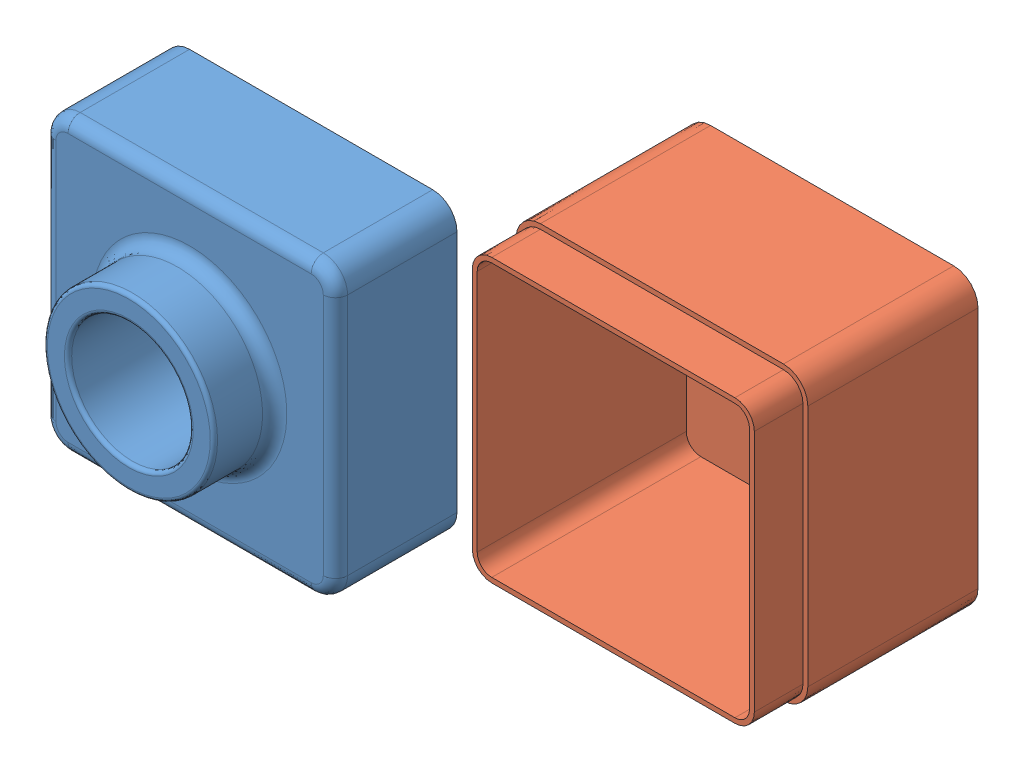
SolidWorks assembly Assem1,2, configuration Default. Lengths in mm.
Overall size (251.55 122.72 157.75).
2 component instances, 2 part files, 0 mates.
Components (placement in the parent):
- Tutorial1-1: Tutorial1 [Default] at (95.7967 88.3661 47.7064) size (120 120 75)
- Tutorial2-1: Tutorial2 [Default] at (158.0177 54.0527 -35.0485) size (120 120 90)
